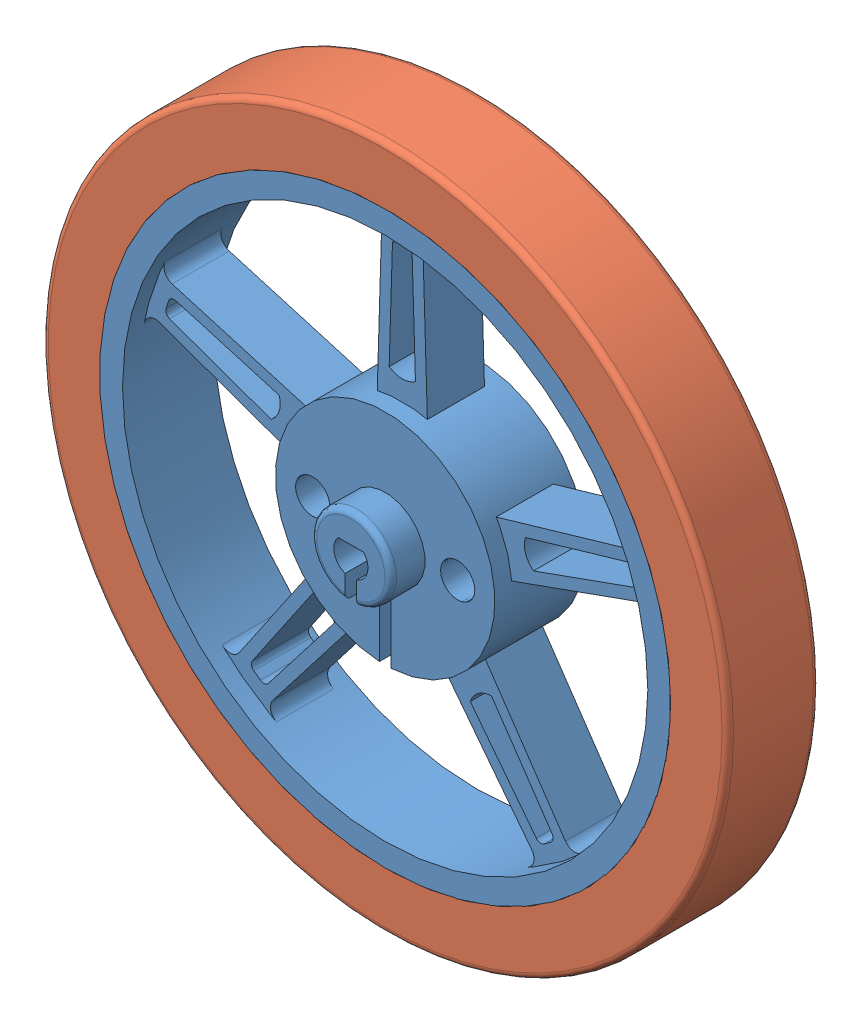
SolidWorks assembly PololuWheel 60x8mm, configuration Predeterminado. Lengths in mm.
Overall size (60 60 11.03).
2 component instances, 2 part files, 4 mates.
Components (placement in the parent):
- Part2^PololuWheel 60x8mm-1: Part2^PololuWheel 60x8mm [Default] x (0 0 -1) z (1 0 0) size (11.03 56 56) (virtual)
- Part3^PololuWheel 60x8mm-1: Part3^PololuWheel 60x8mm [Default] at origin size (60 60 8) (virtual)
Mates (geometry in assembly coordinates):
- InPlace1: in place: plane of Part2^PololuWheel 60x8mm-1 through (0 0 0) normal (1 0 0); moOrthogonalPlaneRef_w of Part2^PololuWheel 60x8mm-1 through (-55 0 0) axis (0 0 1); plane of Part2^PololuWheel 60x8mm-1 through (0 0 0) normal (0 0 -1); unknown of Part2^PololuWheel 60x8mm-1
- Coincident1: coincident aligned: plane of Part2^PololuWheel 60x8mm-1; plane of assembly
- Coincident2: coincident aligned: plane of Part2^PololuWheel 60x8mm-1; moOrthogonalPlaneRef_w of assembly
- Coincident3: coincident anti-aligned: plane of Part2^PololuWheel 60x8mm-1 through (0 0 0) normal (0 0 -1); moOrthogonalPlaneRef_w of assembly
